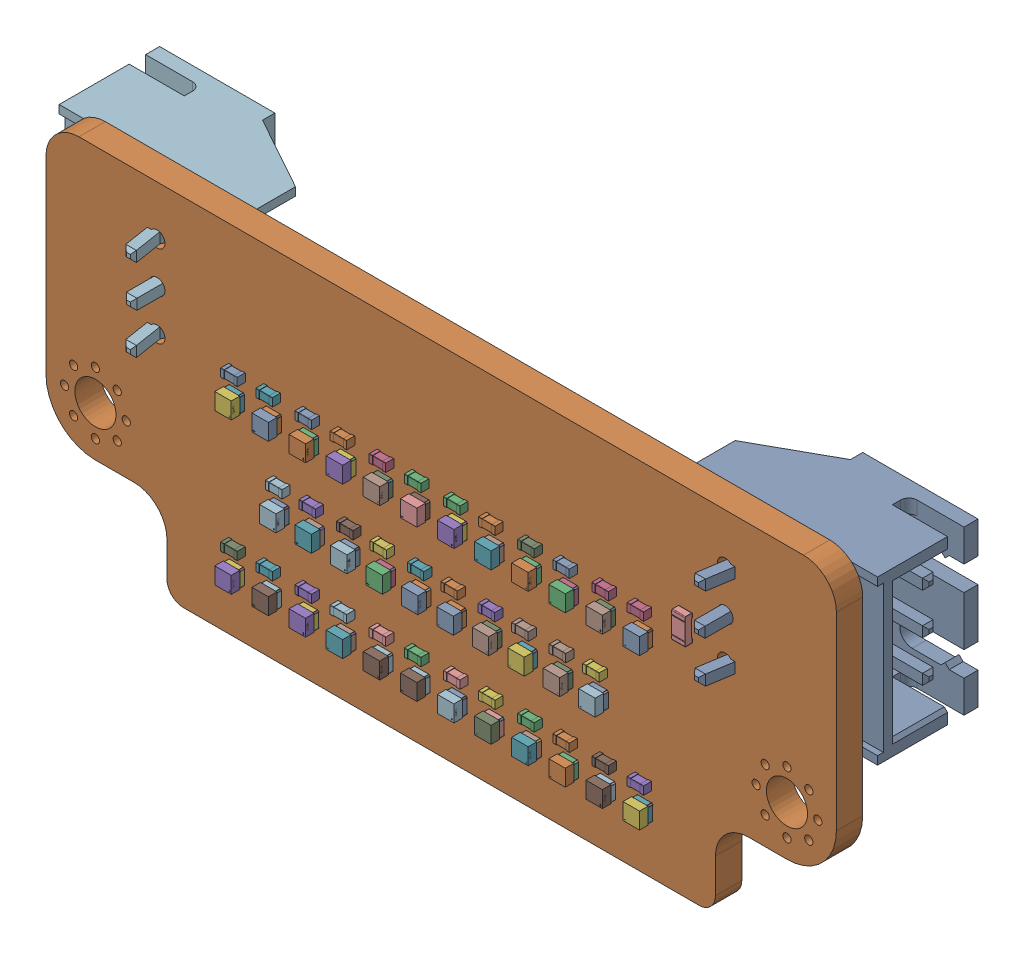
SolidWorks assembly head_logic_display, configuration Default. Lengths in mm.
Overall size (49.7 21.59 9.5).
144 component instances, 5 part files, 0 mates.
Components (placement in the parent):
- head_logic_display(2)-1: head_logic_display(2) [Default] at origin size (49.7 21.59 9.5)
  - LED-SMD_4P-L1.0-W1.0-TL_XL-1010RGBC-WS2812B-1: LED-SMD_4P-L1.0-W1.0-TL_XL-1010RGBC-WS2812B [Default] at (-7.892 -7.295 1.65) x (0 1 0) z (0 0 1) size (1 1 0.81)
    - LED-SMD_4P-L1.0-W1.0-TL_XL-1010RGBC-WS2812B-0-1: LED-SMD_4P-L1.0-W1.0-TL_XL-1010RGBC-WS2812B-0 [Default] at origin size (1 1 0.81)
  - C_0402_1005Metric-1: C_0402_1005Metric [Default] at (-10.206 3.245 1.65) x (-1 0 0) z (0 0 1) size (1 0.5 0.5)
    - C_0402_1005Metric-1-1: C_0402_1005Metric-1 [Default] at origin size (1 0.5 0.5)
  - LED-SMD_4P-L1.0-W1.0-TL_XL-1010RGBC-WS2812B-2: LED-SMD_4P-L1.0-W1.0-TL_XL-1010RGBC-WS2812B [Default] at (9.7 -2.705 1.65) size (1 1 0.81)
    - LED-SMD_4P-L1.0-W1.0-TL_XL-1010RGBC-WS2812B-0-1: LED-SMD_4P-L1.0-W1.0-TL_XL-1010RGBC-WS2812B-0 [Default] at origin size (1 1 0.81)
  - C_0402_1005Metric-2: C_0402_1005Metric [Default] at (7.826 -5.905 1.65) x (-1 0 0) z (0 0 1) size (1 0.5 0.5)
    - C_0402_1005Metric-1-1: C_0402_1005Metric-1 [Default] at origin size (1 0.5 0.5)
  - LED-SMD_4P-L1.0-W1.0-TL_XL-1010RGBC-WS2812B-3: LED-SMD_4P-L1.0-W1.0-TL_XL-1010RGBC-WS2812B [Default] at (-5.638 -7.295 1.65) size (1 1 0.81)
    - LED-SMD_4P-L1.0-W1.0-TL_XL-1010RGBC-WS2812B-0-1: LED-SMD_4P-L1.0-W1.0-TL_XL-1010RGBC-WS2812B-0 [Default] at origin size (1 1 0.81)
  - LED-SMD_4P-L1.0-W1.0-TL_XL-1010RGBC-WS2812B-4: LED-SMD_4P-L1.0-W1.0-TL_XL-1010RGBC-WS2812B [Default] at (1.084 -2.705 1.65) size (1 1 0.81)
    - LED-SMD_4P-L1.0-W1.0-TL_XL-1010RGBC-WS2812B-0-1: LED-SMD_4P-L1.0-W1.0-TL_XL-1010RGBC-WS2812B-0 [Default] at origin size (1 1 0.81)
  - LED-SMD_4P-L1.0-W1.0-TL_XL-1010RGBC-WS2812B-5: LED-SMD_4P-L1.0-W1.0-TL_XL-1010RGBC-WS2812B [Default] at (3.378 1.875 1.65) size (1 1 0.81)
    - LED-SMD_4P-L1.0-W1.0-TL_XL-1010RGBC-WS2812B-0-1: LED-SMD_4P-L1.0-W1.0-TL_XL-1010RGBC-WS2812B-0 [Default] at origin size (1 1 0.81)
  - LED-SMD_4P-L1.0-W1.0-TL_XL-1010RGBC-WS2812B-6: LED-SMD_4P-L1.0-W1.0-TL_XL-1010RGBC-WS2812B [Default] at (-1.07 -2.705 1.65) x (0 1 0) z (0 0 1) size (1 1 0.81)
    - LED-SMD_4P-L1.0-W1.0-TL_XL-1010RGBC-WS2812B-0-1: LED-SMD_4P-L1.0-W1.0-TL_XL-1010RGBC-WS2812B-0 [Default] at origin size (1 1 0.81)
  - LED-SMD_4P-L1.0-W1.0-TL_XL-1010RGBC-WS2812B-7: LED-SMD_4P-L1.0-W1.0-TL_XL-1010RGBC-WS2812B [Default] at (-7.532 -2.705 1.65) size (1 1 0.81)
    - LED-SMD_4P-L1.0-W1.0-TL_XL-1010RGBC-WS2812B-0-1: LED-SMD_4P-L1.0-W1.0-TL_XL-1010RGBC-WS2812B-0 [Default] at origin size (1 1 0.81)
  - LED-SMD_4P-L1.0-W1.0-TL_XL-1010RGBC-WS2812B-8: LED-SMD_4P-L1.0-W1.0-TL_XL-1010RGBC-WS2812B [Default] at (12.394 1.875 1.65) size (1 1 0.81)
    - LED-SMD_4P-L1.0-W1.0-TL_XL-1010RGBC-WS2812B-0-1: LED-SMD_4P-L1.0-W1.0-TL_XL-1010RGBC-WS2812B-0 [Default] at origin size (1 1 0.81)
  - LED-SMD_4P-L1.0-W1.0-TL_XL-1010RGBC-WS2812B-9: LED-SMD_4P-L1.0-W1.0-TL_XL-1010RGBC-WS2812B [Default] at (5.632 -7.295 1.65) x (0 1 0) z (0 0 1) size (1 1 0.81)
    - LED-SMD_4P-L1.0-W1.0-TL_XL-1010RGBC-WS2812B-0-1: LED-SMD_4P-L1.0-W1.0-TL_XL-1010RGBC-WS2812B-0 [Default] at origin size (1 1 0.81)
  - C_0402_1005Metric-3: C_0402_1005Metric [Default] at (-12.34 -5.905 1.65) size (1 0.5 0.5)
    - C_0402_1005Metric-1-1: C_0402_1005Metric-1 [Default] at origin size (1 0.5 0.5)
  - LED-SMD_4P-L1.0-W1.0-TL_XL-1010RGBC-WS2812B-10: LED-SMD_4P-L1.0-W1.0-TL_XL-1010RGBC-WS2812B [Default] at (-7.892 1.875 1.65) x (0 1 0) z (0 0 1) size (1 1 0.81)
    - LED-SMD_4P-L1.0-W1.0-TL_XL-1010RGBC-WS2812B-0-1: LED-SMD_4P-L1.0-W1.0-TL_XL-1010RGBC-WS2812B-0 [Default] at origin size (1 1 0.81)
  - LED-SMD_4P-L1.0-W1.0-TL_XL-1010RGBC-WS2812B-11: LED-SMD_4P-L1.0-W1.0-TL_XL-1010RGBC-WS2812B [Default] at (3.238 -2.705 1.65) x (0 1 0) z (0 0 1) size (1 1 0.81)
    - LED-SMD_4P-L1.0-W1.0-TL_XL-1010RGBC-WS2812B-0-1: LED-SMD_4P-L1.0-W1.0-TL_XL-1010RGBC-WS2812B-0 [Default] at origin size (1 1 0.81)
  - R_0603_1608Metric-1: R_0603_1608Metric [Default] at (14.9 3.645 1.65) x (0 -1 0) z (0 0 1) size (1.6 0.8 0.45)
    - R_0603_1608Metric-2-1: R_0603_1608Metric-2 [Default] at origin size (1.6 0.8 0.45)
  - C_0402_1005Metric-4: C_0402_1005Metric [Default] at (-5.318 -1.305 1.65) size (1 0.5 0.5)
    - C_0402_1005Metric-1-1: C_0402_1005Metric-1 [Default] at origin size (1 0.5 0.5)
  - C_0402_1005Metric-5: C_0402_1005Metric [Default] at (-9.626 -1.305 1.65) size (1 0.5 0.5)
    - C_0402_1005Metric-1-1: C_0402_1005Metric-1 [Default] at origin size (1 0.5 0.5)
  - LED-SMD_4P-L1.0-W1.0-TL_XL-1010RGBC-WS2812B-12: LED-SMD_4P-L1.0-W1.0-TL_XL-1010RGBC-WS2812B [Default] at (-5.638 1.875 1.65) size (1 1 0.81)
    - LED-SMD_4P-L1.0-W1.0-TL_XL-1010RGBC-WS2812B-0-1: LED-SMD_4P-L1.0-W1.0-TL_XL-1010RGBC-WS2812B-0 [Default] at origin size (1 1 0.81)
  - LED-SMD_4P-L1.0-W1.0-TL_XL-1010RGBC-WS2812B-13: LED-SMD_4P-L1.0-W1.0-TL_XL-1010RGBC-WS2812B [Default] at (-1.13 -7.295 1.65) size (1 1 0.81)
    - LED-SMD_4P-L1.0-W1.0-TL_XL-1010RGBC-WS2812B-0-1: LED-SMD_4P-L1.0-W1.0-TL_XL-1010RGBC-WS2812B-0 [Default] at origin size (1 1 0.81)
  - C_0402_1005Metric-6: C_0402_1005Metric [Default] at (7.826 3.245 1.65) x (-1 0 0) z (0 0 1) size (1 0.5 0.5)
    - C_0402_1005Metric-1-1: C_0402_1005Metric-1 [Default] at origin size (1 0.5 0.5)
  - LED-SMD_4P-L1.0-W1.0-TL_XL-1010RGBC-WS2812B-14: LED-SMD_4P-L1.0-W1.0-TL_XL-1010RGBC-WS2812B [Default] at (-12.4 1.875 1.65) x (0 1 0) z (0 0 1) size (1 1 0.81)
    - LED-SMD_4P-L1.0-W1.0-TL_XL-1010RGBC-WS2812B-0-1: LED-SMD_4P-L1.0-W1.0-TL_XL-1010RGBC-WS2812B-0 [Default] at origin size (1 1 0.81)
  - C_0402_1005Metric-7: C_0402_1005Metric [Default] at (5.332 -1.305 1.65) x (-1 0 0) z (0 0 1) size (1 0.5 0.5)
    - C_0402_1005Metric-1-1: C_0402_1005Metric-1 [Default] at origin size (1 0.5 0.5)
  - C_0402_1005Metric-8: C_0402_1005Metric [Default] at (5.692 3.245 1.65) size (1 0.5 0.5)
    - C_0402_1005Metric-1-1: C_0402_1005Metric-1 [Default] at origin size (1 0.5 0.5)
  - LED-SMD_4P-L1.0-W1.0-TL_XL-1010RGBC-WS2812B-15: LED-SMD_4P-L1.0-W1.0-TL_XL-1010RGBC-WS2812B [Default] at (5.632 1.875 1.65) x (0 1 0) z (0 0 1) size (1 1 0.81)
    - LED-SMD_4P-L1.0-W1.0-TL_XL-1010RGBC-WS2812B-0-1: LED-SMD_4P-L1.0-W1.0-TL_XL-1010RGBC-WS2812B-0 [Default] at origin size (1 1 0.81)
  - LED-SMD_4P-L1.0-W1.0-TL_XL-1010RGBC-WS2812B-16: LED-SMD_4P-L1.0-W1.0-TL_XL-1010RGBC-WS2812B [Default] at (7.546 -2.705 1.65) x (0 1 0) z (0 0 1) size (1 1 0.81)
    - LED-SMD_4P-L1.0-W1.0-TL_XL-1010RGBC-WS2812B-0-1: LED-SMD_4P-L1.0-W1.0-TL_XL-1010RGBC-WS2812B-0 [Default] at origin size (1 1 0.81)
  - C_0402_1005Metric-9: C_0402_1005Metric [Default] at (1.184 -5.905 1.65) size (1 0.5 0.5)
    - C_0402_1005Metric-1-1: C_0402_1005Metric-1 [Default] at origin size (1 0.5 0.5)
  - LED-SMD_4P-L1.0-W1.0-TL_XL-1010RGBC-WS2812B-17: LED-SMD_4P-L1.0-W1.0-TL_XL-1010RGBC-WS2812B [Default] at (-3.224 -2.705 1.65) size (1 1 0.81)
    - LED-SMD_4P-L1.0-W1.0-TL_XL-1010RGBC-WS2812B-0-1: LED-SMD_4P-L1.0-W1.0-TL_XL-1010RGBC-WS2812B-0 [Default] at origin size (1 1 0.81)
  - C_0402_1005Metric-10: C_0402_1005Metric [Default] at (-7.832 -5.905 1.65) size (1 0.5 0.5)
    - C_0402_1005Metric-1-1: C_0402_1005Metric-1 [Default] at origin size (1 0.5 0.5)
  - C_0402_1005Metric-11: C_0402_1005Metric [Default] at (3.318 -5.905 1.65) x (-1 0 0) z (0 0 1) size (1 0.5 0.5)
    - C_0402_1005Metric-1-1: C_0402_1005Metric-1 [Default] at origin size (1 0.5 0.5)
  - C_0402_1005Metric-12: C_0402_1005Metric [Default] at (-10.206 -5.905 1.65) x (-1 0 0) z (0 0 1) size (1 0.5 0.5)
    - C_0402_1005Metric-1-1: C_0402_1005Metric-1 [Default] at origin size (1 0.5 0.5)
  - LED-SMD_4P-L1.0-W1.0-TL_XL-1010RGBC-WS2812B-18: LED-SMD_4P-L1.0-W1.0-TL_XL-1010RGBC-WS2812B [Default] at (-5.378 -2.705 1.65) x (0 1 0) z (0 0 1) size (1 1 0.81)
    - LED-SMD_4P-L1.0-W1.0-TL_XL-1010RGBC-WS2812B-0-1: LED-SMD_4P-L1.0-W1.0-TL_XL-1010RGBC-WS2812B-0 [Default] at origin size (1 1 0.81)
  - LED-SMD_4P-L1.0-W1.0-TL_XL-1010RGBC-WS2812B-19: LED-SMD_4P-L1.0-W1.0-TL_XL-1010RGBC-WS2812B [Default] at (5.392 -2.705 1.65) size (1 1 0.81)
    - LED-SMD_4P-L1.0-W1.0-TL_XL-1010RGBC-WS2812B-0-1: LED-SMD_4P-L1.0-W1.0-TL_XL-1010RGBC-WS2812B-0 [Default] at origin size (1 1 0.81)
  - LED-SMD_4P-L1.0-W1.0-TL_XL-1010RGBC-WS2812B-20: LED-SMD_4P-L1.0-W1.0-TL_XL-1010RGBC-WS2812B [Default] at (1.124 -7.295 1.65) x (0 1 0) z (0 0 1) size (1 1 0.81)
    - LED-SMD_4P-L1.0-W1.0-TL_XL-1010RGBC-WS2812B-0-1: LED-SMD_4P-L1.0-W1.0-TL_XL-1010RGBC-WS2812B-0 [Default] at origin size (1 1 0.81)
  - C_0402_1005Metric-13: C_0402_1005Metric [Default] at (-5.698 3.245 1.65) x (-1 0 0) z (0 0 1) size (1 0.5 0.5)
    - C_0402_1005Metric-1-1: C_0402_1005Metric-1 [Default] at origin size (1 0.5 0.5)
  - C_0402_1005Metric-14: C_0402_1005Metric [Default] at (5.692 -5.905 1.65) size (1 0.5 0.5)
    - C_0402_1005Metric-1-1: C_0402_1005Metric-1 [Default] at origin size (1 0.5 0.5)
  - C_0402_1005Metric-15: C_0402_1005Metric [Default] at (12.334 3.245 1.65) x (-1 0 0) z (0 0 1) size (1 0.5 0.5)
    - C_0402_1005Metric-1-1: C_0402_1005Metric-1 [Default] at origin size (1 0.5 0.5)
  - C_0402_1005Metric-16: C_0402_1005Metric [Default] at (3.298 -1.305 1.65) size (1 0.5 0.5)
    - C_0402_1005Metric-1-1: C_0402_1005Metric-1 [Default] at origin size (1 0.5 0.5)
  - C_0402_1005Metric-17: C_0402_1005Metric [Default] at (-3.284 -1.305 1.65) x (-1 0 0) z (0 0 1) size (1 0.5 0.5)
    - C_0402_1005Metric-1-1: C_0402_1005Metric-1 [Default] at origin size (1 0.5 0.5)
  - LED-SMD_4P-L1.0-W1.0-TL_XL-1010RGBC-WS2812B-21: LED-SMD_4P-L1.0-W1.0-TL_XL-1010RGBC-WS2812B [Default] at (-3.384 -7.295 1.65) x (0 1 0) z (0 0 1) size (1 1 0.81)
    - LED-SMD_4P-L1.0-W1.0-TL_XL-1010RGBC-WS2812B-0-1: LED-SMD_4P-L1.0-W1.0-TL_XL-1010RGBC-WS2812B-0 [Default] at origin size (1 1 0.81)
  - LED-SMD_4P-L1.0-W1.0-TL_XL-1010RGBC-WS2812B-22: LED-SMD_4P-L1.0-W1.0-TL_XL-1010RGBC-WS2812B [Default] at (1.124 1.875 1.65) x (0 1 0) z (0 0 1) size (1 1 0.81)
    - LED-SMD_4P-L1.0-W1.0-TL_XL-1010RGBC-WS2812B-0-1: LED-SMD_4P-L1.0-W1.0-TL_XL-1010RGBC-WS2812B-0 [Default] at origin size (1 1 0.81)
  - LED-SMD_4P-L1.0-W1.0-TL_XL-1010RGBC-WS2812B-23: LED-SMD_4P-L1.0-W1.0-TL_XL-1010RGBC-WS2812B [Default] at (10.14 -7.295 1.65) x (0 1 0) z (0 0 1) size (1 1 0.81)
    - LED-SMD_4P-L1.0-W1.0-TL_XL-1010RGBC-WS2812B-0-1: LED-SMD_4P-L1.0-W1.0-TL_XL-1010RGBC-WS2812B-0 [Default] at origin size (1 1 0.81)
  - LED-SMD_4P-L1.0-W1.0-TL_XL-1010RGBC-WS2812B-24: LED-SMD_4P-L1.0-W1.0-TL_XL-1010RGBC-WS2812B [Default] at (-12.4 -7.295 1.65) x (0 1 0) z (0 0 1) size (1 1 0.81)
    - LED-SMD_4P-L1.0-W1.0-TL_XL-1010RGBC-WS2812B-0-1: LED-SMD_4P-L1.0-W1.0-TL_XL-1010RGBC-WS2812B-0 [Default] at origin size (1 1 0.81)
  - LED-SMD_4P-L1.0-W1.0-TL_XL-1010RGBC-WS2812B-25: LED-SMD_4P-L1.0-W1.0-TL_XL-1010RGBC-WS2812B [Default] at (-10.146 -7.295 1.65) size (1 1 0.81)
    - LED-SMD_4P-L1.0-W1.0-TL_XL-1010RGBC-WS2812B-0-1: LED-SMD_4P-L1.0-W1.0-TL_XL-1010RGBC-WS2812B-0 [Default] at origin size (1 1 0.81)
  - C_0402_1005Metric-18: C_0402_1005Metric [Default] at (-12.34 3.245 1.65) size (1 0.5 0.5)
    - C_0402_1005Metric-1-1: C_0402_1005Metric-1 [Default] at origin size (1 0.5 0.5)
  - C_0402_1005Metric-19: C_0402_1005Metric [Default] at (3.318 3.245 1.65) x (-1 0 0) z (0 0 1) size (1 0.5 0.5)
    - C_0402_1005Metric-1-1: C_0402_1005Metric-1 [Default] at origin size (1 0.5 0.5)
  - C_0402_1005Metric-20: C_0402_1005Metric [Default] at (-1.19 3.245 1.65) x (-1 0 0) z (0 0 1) size (1 0.5 0.5)
    - C_0402_1005Metric-1-1: C_0402_1005Metric-1 [Default] at origin size (1 0.5 0.5)
  - C_0402_1005Metric-21: C_0402_1005Metric [Default] at (-3.324 3.245 1.65) size (1 0.5 0.5)
    - C_0402_1005Metric-1-1: C_0402_1005Metric-1 [Default] at origin size (1 0.5 0.5)
  - C_0402_1005Metric-22: C_0402_1005Metric [Default] at (-7.592 -1.305 1.65) x (-1 0 0) z (0 0 1) size (1 0.5 0.5)
    - C_0402_1005Metric-1-1: C_0402_1005Metric-1 [Default] at origin size (1 0.5 0.5)
  - C_0402_1005Metric-23: C_0402_1005Metric [Default] at (9.64 -1.305 1.65) x (-1 0 0) z (0 0 1) size (1 0.5 0.5)
    - C_0402_1005Metric-1-1: C_0402_1005Metric-1 [Default] at origin size (1 0.5 0.5)
  - C_0402_1005Metric-24: C_0402_1005Metric [Default] at (-1.01 -1.305 1.65) size (1 0.5 0.5)
    - C_0402_1005Metric-1-1: C_0402_1005Metric-1 [Default] at origin size (1 0.5 0.5)
  - LED-SMD_4P-L1.0-W1.0-TL_XL-1010RGBC-WS2812B-26: LED-SMD_4P-L1.0-W1.0-TL_XL-1010RGBC-WS2812B [Default] at (-9.686 -2.705 1.65) x (0 1 0) z (0 0 1) size (1 1 0.81)
    - LED-SMD_4P-L1.0-W1.0-TL_XL-1010RGBC-WS2812B-0-1: LED-SMD_4P-L1.0-W1.0-TL_XL-1010RGBC-WS2812B-0 [Default] at origin size (1 1 0.81)
  - LED-SMD_4P-L1.0-W1.0-TL_XL-1010RGBC-WS2812B-27: LED-SMD_4P-L1.0-W1.0-TL_XL-1010RGBC-WS2812B [Default] at (12.394 -7.295 1.65) size (1 1 0.81)
    - LED-SMD_4P-L1.0-W1.0-TL_XL-1010RGBC-WS2812B-0-1: LED-SMD_4P-L1.0-W1.0-TL_XL-1010RGBC-WS2812B-0 [Default] at origin size (1 1 0.81)
  - C_0402_1005Metric-25: C_0402_1005Metric [Default] at (7.606 -1.305 1.65) size (1 0.5 0.5)
    - C_0402_1005Metric-1-1: C_0402_1005Metric-1 [Default] at origin size (1 0.5 0.5)
  - LED-SMD_4P-L1.0-W1.0-TL_XL-1010RGBC-WS2812B-28: LED-SMD_4P-L1.0-W1.0-TL_XL-1010RGBC-WS2812B [Default] at (-10.146 1.875 1.65) size (1 1 0.81)
    - LED-SMD_4P-L1.0-W1.0-TL_XL-1010RGBC-WS2812B-0-1: LED-SMD_4P-L1.0-W1.0-TL_XL-1010RGBC-WS2812B-0 [Default] at origin size (1 1 0.81)
  - C_0402_1005Metric-26: C_0402_1005Metric [Default] at (-1.19 -5.905 1.65) x (-1 0 0) z (0 0 1) size (1 0.5 0.5)
    - C_0402_1005Metric-1-1: C_0402_1005Metric-1 [Default] at origin size (1 0.5 0.5)
  - LED-SMD_4P-L1.0-W1.0-TL_XL-1010RGBC-WS2812B-29: LED-SMD_4P-L1.0-W1.0-TL_XL-1010RGBC-WS2812B [Default] at (-3.384 1.875 1.65) x (0 1 0) z (0 0 1) size (1 1 0.81)
    - LED-SMD_4P-L1.0-W1.0-TL_XL-1010RGBC-WS2812B-0-1: LED-SMD_4P-L1.0-W1.0-TL_XL-1010RGBC-WS2812B-0 [Default] at origin size (1 1 0.81)
  - LED-SMD_4P-L1.0-W1.0-TL_XL-1010RGBC-WS2812B-30: LED-SMD_4P-L1.0-W1.0-TL_XL-1010RGBC-WS2812B [Default] at (7.886 -7.295 1.65) size (1 1 0.81)
    - LED-SMD_4P-L1.0-W1.0-TL_XL-1010RGBC-WS2812B-0-1: LED-SMD_4P-L1.0-W1.0-TL_XL-1010RGBC-WS2812B-0 [Default] at origin size (1 1 0.81)
  - C_0402_1005Metric-27: C_0402_1005Metric [Default] at (10.2 3.245 1.65) size (1 0.5 0.5)
    - C_0402_1005Metric-1-1: C_0402_1005Metric-1 [Default] at origin size (1 0.5 0.5)
  - C_0402_1005Metric-28: C_0402_1005Metric [Default] at (12.334 -5.905 1.65) x (-1 0 0) z (0 0 1) size (1 0.5 0.5)
    - C_0402_1005Metric-1-1: C_0402_1005Metric-1 [Default] at origin size (1 0.5 0.5)
  - LED-SMD_4P-L1.0-W1.0-TL_XL-1010RGBC-WS2812B-31: LED-SMD_4P-L1.0-W1.0-TL_XL-1010RGBC-WS2812B [Default] at (-1.13 1.875 1.65) size (1 1 0.81)
    - LED-SMD_4P-L1.0-W1.0-TL_XL-1010RGBC-WS2812B-0-1: LED-SMD_4P-L1.0-W1.0-TL_XL-1010RGBC-WS2812B-0 [Default] at origin size (1 1 0.81)
  - C_0402_1005Metric-29: C_0402_1005Metric [Default] at (-5.698 -5.905 1.65) x (-1 0 0) z (0 0 1) size (1 0.5 0.5)
    - C_0402_1005Metric-1-1: C_0402_1005Metric-1 [Default] at origin size (1 0.5 0.5)
  - C_0402_1005Metric-30: C_0402_1005Metric [Default] at (-7.832 3.245 1.65) size (1 0.5 0.5)
    - C_0402_1005Metric-1-1: C_0402_1005Metric-1 [Default] at origin size (1 0.5 0.5)
  - C_0402_1005Metric-31: C_0402_1005Metric [Default] at (1.024 -1.305 1.65) x (-1 0 0) z (0 0 1) size (1 0.5 0.5)
    - C_0402_1005Metric-1-1: C_0402_1005Metric-1 [Default] at origin size (1 0.5 0.5)
  - C_0402_1005Metric-32: C_0402_1005Metric [Default] at (1.184 3.245 1.65) size (1 0.5 0.5)
    - C_0402_1005Metric-1-1: C_0402_1005Metric-1 [Default] at origin size (1 0.5 0.5)
  - LED-SMD_4P-L1.0-W1.0-TL_XL-1010RGBC-WS2812B-32: LED-SMD_4P-L1.0-W1.0-TL_XL-1010RGBC-WS2812B [Default] at (10.14 1.875 1.65) x (0 1 0) z (0 0 1) size (1 1 0.81)
    - LED-SMD_4P-L1.0-W1.0-TL_XL-1010RGBC-WS2812B-0-1: LED-SMD_4P-L1.0-W1.0-TL_XL-1010RGBC-WS2812B-0 [Default] at origin size (1 1 0.81)
  - C_0402_1005Metric-33: C_0402_1005Metric [Default] at (-3.324 -5.905 1.65) size (1 0.5 0.5)
    - C_0402_1005Metric-1-1: C_0402_1005Metric-1 [Default] at origin size (1 0.5 0.5)
  - LED-SMD_4P-L1.0-W1.0-TL_XL-1010RGBC-WS2812B-33: LED-SMD_4P-L1.0-W1.0-TL_XL-1010RGBC-WS2812B [Default] at (7.886 1.875 1.65) size (1 1 0.81)
    - LED-SMD_4P-L1.0-W1.0-TL_XL-1010RGBC-WS2812B-0-1: LED-SMD_4P-L1.0-W1.0-TL_XL-1010RGBC-WS2812B-0 [Default] at origin size (1 1 0.81)
  - LED-SMD_4P-L1.0-W1.0-TL_XL-1010RGBC-WS2812B-34: LED-SMD_4P-L1.0-W1.0-TL_XL-1010RGBC-WS2812B [Default] at (3.378 -7.295 1.65) size (1 1 0.81)
    - LED-SMD_4P-L1.0-W1.0-TL_XL-1010RGBC-WS2812B-0-1: LED-SMD_4P-L1.0-W1.0-TL_XL-1010RGBC-WS2812B-0 [Default] at origin size (1 1 0.81)
  - C_0402_1005Metric-34: C_0402_1005Metric [Default] at (10.2 -5.905 1.65) size (1 0.5 0.5)
    - C_0402_1005Metric-1-1: C_0402_1005Metric-1 [Default] at origin size (1 0.5 0.5)
  - JST_XH_S3B-XH-A-1_1x03_P2.50mm_Horizontal-1: JST_XH_S3B-XH-A-1_1x03_P2.50mm_Horizontal [Default] at (-17.25 2.795 -0.05) x (0 1 0) z (0 0 -1) size (9.9 11.5 9.5)
    - JST_S3B_XH_A_1-1: JST_S3B_XH_A_1 [Default] at origin size (9.9 11.5 9.5)
  - JST_XH_S3B-XH-A-1_1x03_P2.50mm_Horizontal-2: JST_XH_S3B-XH-A-1_1x03_P2.50mm_Horizontal [Default] at (17.25 7.795 -0.05) x (0 -1 0) z (0 0 -1) size (9.9 11.5 9.5)
    - JST_S3B_XH_A_1-1: JST_S3B_XH_A_1 [Default] at origin size (9.9 11.5 9.5)
  - head_logic_display_PCB-1: head_logic_display_PCB [Default] at origin size (48 21.59 1.6)
